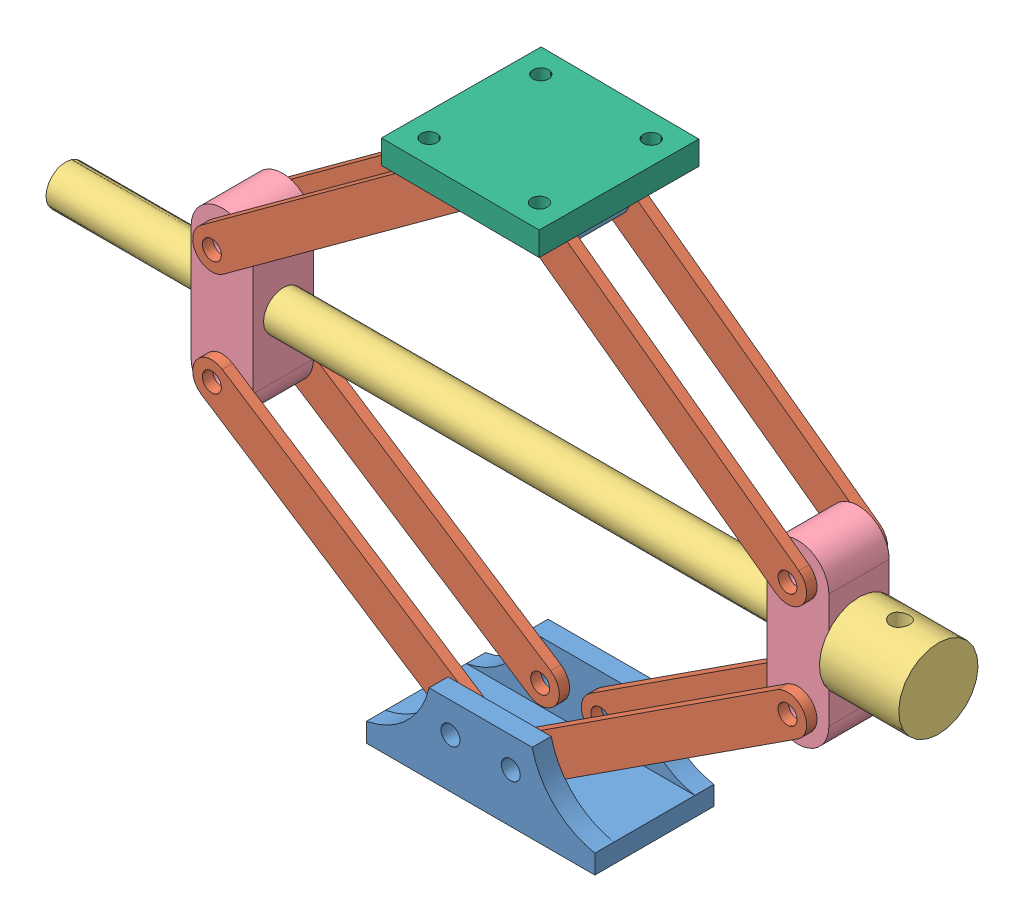
SolidWorks assembly Assem1, configuration Default. Lengths in mm.
Overall size (550 347.37 100.61).
14 component instances, 6 part files, 28 mates.
Components (placement in the parent):
- Part1-1: Part1 [Default] at (94.1493 67.4865 39.9347) size (144 50 75)
- Part2-1: Part2 [Default] at (-87.2931 204.0053 58.4347) x (0.838606 -0.544739 0) z (0.544739 0.838606 0) size (217.92 6.5 24.21)
- Part3-1: Part3 [Default] at (345.1694 240.0698 77.4347) x (-1 0 0) z (0 0.999421 -0.034029) size (550 50 50)
- Part4-1: Part4 [Default] at (275.5916 204.0053 58.4347) x (0 1 0) z (1 0 0) size (111.28 38 39.16)
- Part5-1: Part5 [Default] at (69.1493 390.36 96.4347) x (1 0 0) z (0 1 0) size (75 38 25)
- Part2-2: Part2 [Default] at (275.5916 204.0053 102.9347) x (-0.838606 -0.544739 0) z (0.544739 -0.838606 0) size (217.92 6.5 24.21)
- Part2-3: Part2 [Default] at (75.1493 98.4865 102.9347) x (-0.838606 0.544739 0) z (-0.544739 -0.838606 0) size (217.92 6.5 24.21)
- Part2-4: Part2 [Default] at (69.1493 390.36 51.9347) x (-0.807631 -0.589689 0) z (-0.589689 0.807631 0) size (217.92 6.5 24.21)
- Part2-5: Part2 [Default] at (275.5916 204.0053 58.4347) x (-0.838606 -0.544739 0) z (0.544739 -0.838606 0) size (217.92 6.5 24.21)
- Part4-2: Part4 [Default] at (-87.2931 204.0053 96.4347) x (0 1 0) z (-1 0 0) size (111.28 38 39.16)
- Part2-6: Part2 [Default] at (69.1493 390.36 102.9347) x (-0.807631 -0.589689 0) z (0.589689 -0.807631 0) size (217.92 6.5 24.21)
- Part2-7: Part2 [Default] at (275.5916 276.1342 102.9347) x (-0.807631 0.589689 0) z (-0.589689 -0.807631 0) size (217.92 6.5 24.21)
- Part2-8: Part2 [Default] at (275.5916 276.1342 51.9347) x (-0.807631 0.589689 0) z (0.589689 0.807631 0) size (217.92 6.5 24.21)
- Part6-1: Part6 [Default] at (94.1493 377.86 77.4347) x (0.999982 0 0.006081) z (-0.006081 0 0.999982) size (100 37 100)
Mates (geometry in assembly coordinates):
- Coincident2: coincident anti-aligned: circle of Part1-1; circle of Part2-5
- Coincident3: coincident aligned: circle of Part1-1; circle of Part2-1
- Coincident6: coincident anti-aligned: circle of Part1-1; circle of Part2-2
- Coincident7: coincident aligned: circle of Part1-1; circle of Part2-3
- Coincident8: coincident aligned: circle of Part2-1; circle of Part4-2
- Coincident9: coincident aligned: circle of Part2-3; circle of Part4-2
- Coincident10: coincident anti-aligned: circle of Part4-1; circle of Part2-2
- Coincident11: coincident anti-aligned: circle of Part4-1; circle of Part2-5
- Coincident12: coincident anti-aligned: circle of Part2-4; circle of Part4-2
- Coincident13: coincident aligned: circle of Part4-1; circle of Part2-8
- Coincident14: coincident aligned: circle of Part4-2; circle of Part2-6
- Coincident15: coincident anti-aligned: circle of Part4-1; circle of Part2-7
- Coincident16: coincident anti-aligned: circle of Part5-1; circle of Part2-4
- Coincident17: coincident aligned: circle of Part5-1; circle of Part2-7
- Coincident18: coincident aligned: circle of Part5-1; circle of Part2-6
- Coincident19: coincident anti-aligned: circle of Part5-1; circle of Part2-8
- Concentric1: concentric aligned: cylinder of Part3-1 through (-201.3222 234.4613 77.4347) axis (1 0 0) radius 12.5; cylinder of Part4-1 through (200.6778 234.4613 77.4347) axis (1 0 0) radius 12
- Concentric3: concentric anti-aligned: cylinder of Part3-1 through (-201.3222 234.4613 77.4347) axis (1 0 0) radius 12.5; cylinder of Part4-2 through (-12.3793 234.4613 77.4347) axis (-1 0 0) radius 12
- Coincident20: coincident anti-aligned: plane of Part3-1 through (298.6778 234.4613 77.4347) normal (-1 0 0); plane of Part4-1 through (298.6778 198.3969 96.4347) normal (1 0 0)
- Parallel5: parallel aligned: plane of Part1-1 through (22.1493 79.4865 51.9347) normal (0 1 0); plane of Part5-1 through (69.1493 392.2846 58.4347) normal (0 1 0)
- Concentric5: concentric anti-aligned: cylinder of Part5-1 through (94.1493 354.2846 77.4347) axis (0 1 0) radius 6; cylinder of Part6-1 through (94.1493 389.2846 77.4347) axis (0 -1 0) radius 6
- Coincident24: coincident aligned: plane of Part5-1 through (69.1493 367.2846 58.4347) normal (0 -1 0); plane of Part6-1 through (94.1493 367.2846 77.4347) normal (0 -1 0)
- Parallel6: parallel anti-aligned: plane of Part4-1 through (259.5222 198.3969 96.4347) normal (-1 0 0); plane of Part4-2 through (-71.2237 198.3969 58.4347) normal (1 0 0)
- Perpendicular1: perpendicular: plane of Part1-1 through (22.1493 79.4865 51.9347) normal (0 1 0); plane of Part4-2 through (-71.2237 198.3969 58.4347) normal (1 0 0)
- Perpendicular2: perpendicular: plane of Part1-1 through (22.1493 79.4865 51.9347) normal (0 1 0); plane of Part4-1 through (259.5222 198.3969 96.4347) normal (-1 0 0)
- Perpendicular3: perpendicular: plane of Part5-1 through (69.1493 355.3802 58.4347) normal (0 -1 0); plane of Part4-2 through (-74.8823 192.0514 58.4347) normal (1 0 0)
- Perpendicular4: perpendicular: plane of Part4-1 through (263.1808 192.0514 96.4347) normal (-1 0 0); plane of Part5-1 through (69.1493 355.3802 58.4347) normal (0 -1 0)
- Perpendicular5: perpendicular: plane of Part4-1 through (263.1808 192.0514 96.4347) normal (-1 0 0); plane of Part5-1 through (69.1493 355.3802 58.4347) normal (0 -1 0)
